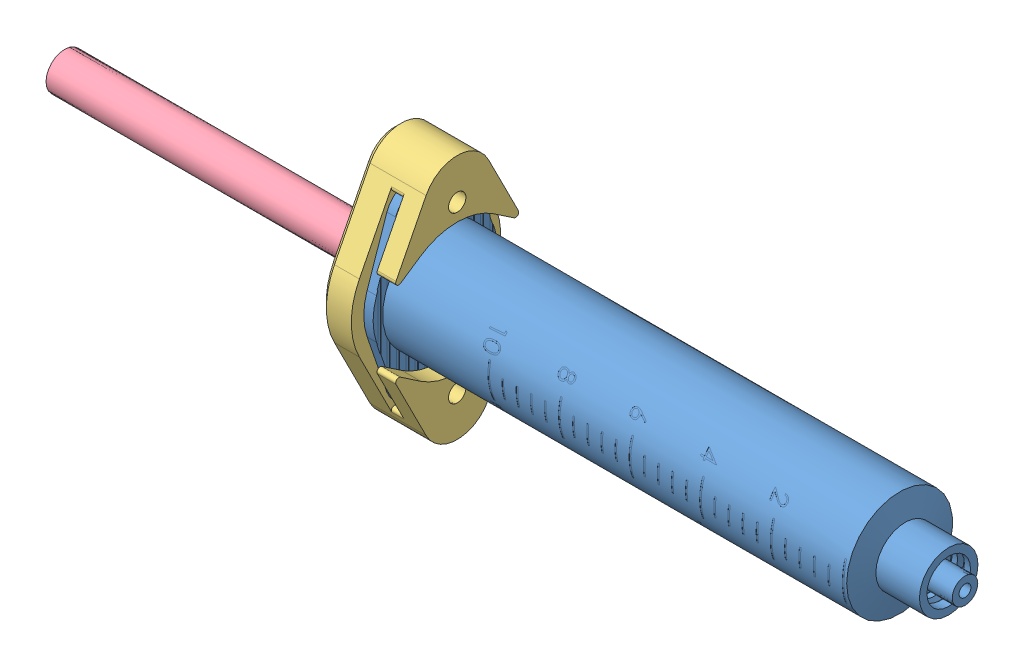
SolidWorks assembly syringe-nozzle, configuration Default. Lengths in mm.
Overall size (144.5 39.5 24).
4 component instances, 4 part files, 12 mates.
Components (placement in the parent):
- syringe-cylinder-10ml-1: syringe-cylinder-10ml [Default] at origin size (86.5 31 20)
- rubber-10ml-1: rubber-10ml [Default] at (5.75 0 0) x (-1 0 0) z (0 0.519313 0.854584) size (8.54 15 15)
- syringe-adapter-10ml-v2-1: syringe-adapter-10ml-v2 [Default] at (-5 0 0) x (0 0 -1) z (0 1 0) size (24 16 39.5)
- straight-tube-6mm-1: straight-tube-6mm [Default] at (-8 0 0) x (0 1 0) z (0 0 1) size (6 50 6)
Mates (geometry in assembly coordinates):
- Concentric2: concentric aligned: cylinder of syringe-cylinder-10ml-1 through (103.5215 0 0) axis (1 0 0) radius 7.5; cone of rubber-10ml-1 through (-3.25 0 0) axis (1 0 0)
- Coincident3: coincident: plane of rubber-10ml-1 through (-0.75 -6.4094 3.8948) normal (-1 0 0); plane of syringe-adapter-10ml-v2-1 through (-0.75 7.75 0) normal (1 0 0)
- Coincident4: coincident anti-aligned: plane of syringe-cylinder-10ml-1 through (0 7.3 0) normal (-1 0 0); plane of syringe-adapter-10ml-v2-1 through (0 1.5 0) normal (1 0 0)
- Coincident5: coincident anti-aligned: plane of syringe-cylinder-10ml-1 through (0 0 0) normal (0 0 1); plane of syringe-adapter-10ml-v2-1 through (-5 0 0) normal (0 0 -1)
- Coincident6: coincident: plane of syringe-adapter-10ml-v2-1 through (-8 2 0) normal (-1 0 0); plane of straight-tube-6mm-1 through (-8 0 0) normal (1 0 0)
- Concentric6: concentric: cylinder of syringe-adapter-10ml-v2-1 through (-15.88 0 0) axis (-1 0 0) radius 3.2; cylinder of straight-tube-6mm-1 through (-58 0 0) axis (1 0 0) radius 3
- Coincident7: coincident aligned: plane of syringe-cylinder-10ml-1 through (0 0 0) normal (0 0 1)
- Coincident8: coincident aligned: plane of syringe-cylinder-10ml-1 through (0 0 0) normal (1 0 0)
- Coincident9: coincident aligned: plane of syringe-cylinder-10ml-1 through (0 0 0) normal (0 1 0)
- Coincident10: coincident anti-aligned: plane of syringe-adapter-10ml-v2-1 through (-8 2 0) normal (-1 0 0); plane of syringe-adapter-cap-1 through (-8 0 0) normal (1 0 0)
- Concentric7: concentric anti-aligned: cylinder of syringe-adapter-10ml-v2-1 through (-15.88 0 0) axis (-1 0 0) radius 4.2; cylinder of syringe-adapter-cap-1 through (-14.5 0 0) axis (1 0 0) radius 6.5
- Concentric8: concentric anti-aligned: cylinder of syringe-cylinder-10ml-1 through (103.5215 0 0) axis (1 0 0) radius 8.5; cylinder of syringe-adapter-10ml-v2-1 through (-12.88 0 0) axis (-1 0 0) radius 1.5
